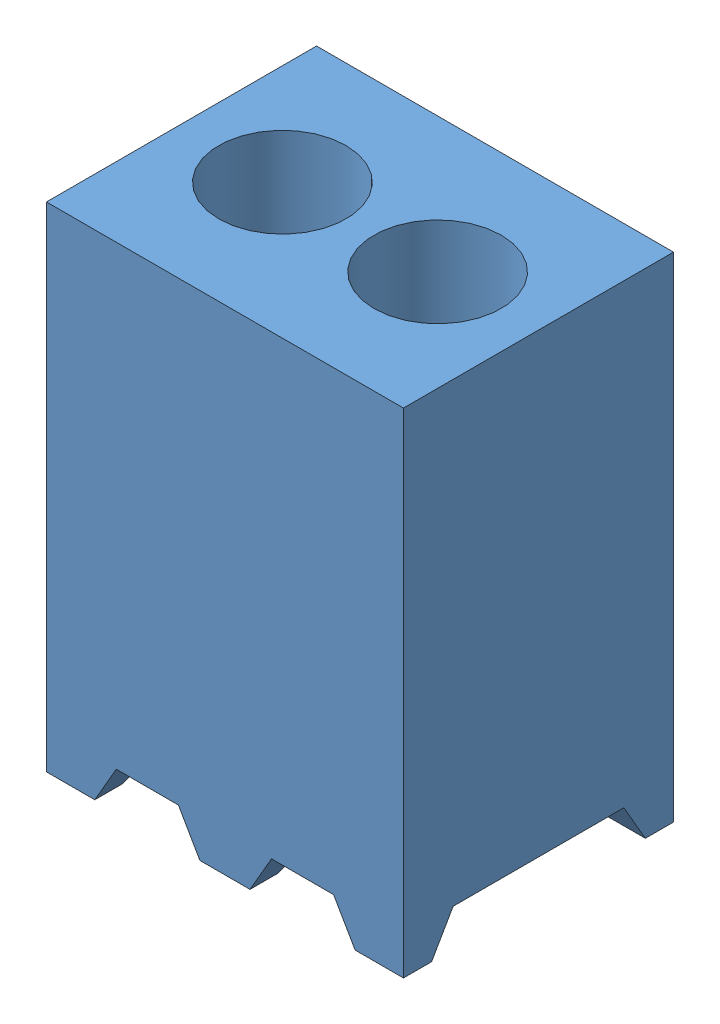
SolidWorks assembly mill-max-854-22-002-10-003101, configuration Default. Lengths in mm.
Overall size (2.92 7.9 2.21).
3 component instances, 2 part files, 0 mates.
Components (placement in the parent):
- mill-max-854-22-002-10-003101_P8XX-18-013-02-000000(P802-18-013-02-000000)-1: mill-max-854-22-002-10-003101_P8XX-18-013-02-000000(P802-18-013-02-000000) [Default] at origin size (2.92 4.04 2.21)
- mill-max-854-22-002-10-003101_0955_compressed-1: mill-max-854-22-002-10-003101_0955_compressed [Default] at (0.8255 2.667 -1.1049) x (0 -1 0) z (-1 0 0) size (7.9 1.14 1.14)
- mill-max-854-22-002-10-003101_0955_compressed-2: mill-max-854-22-002-10-003101_0955_compressed [Default] at (2.0955 2.667 -1.1049) x (0 -1 0) z (-1 0 0) size (7.9 1.14 1.14)
